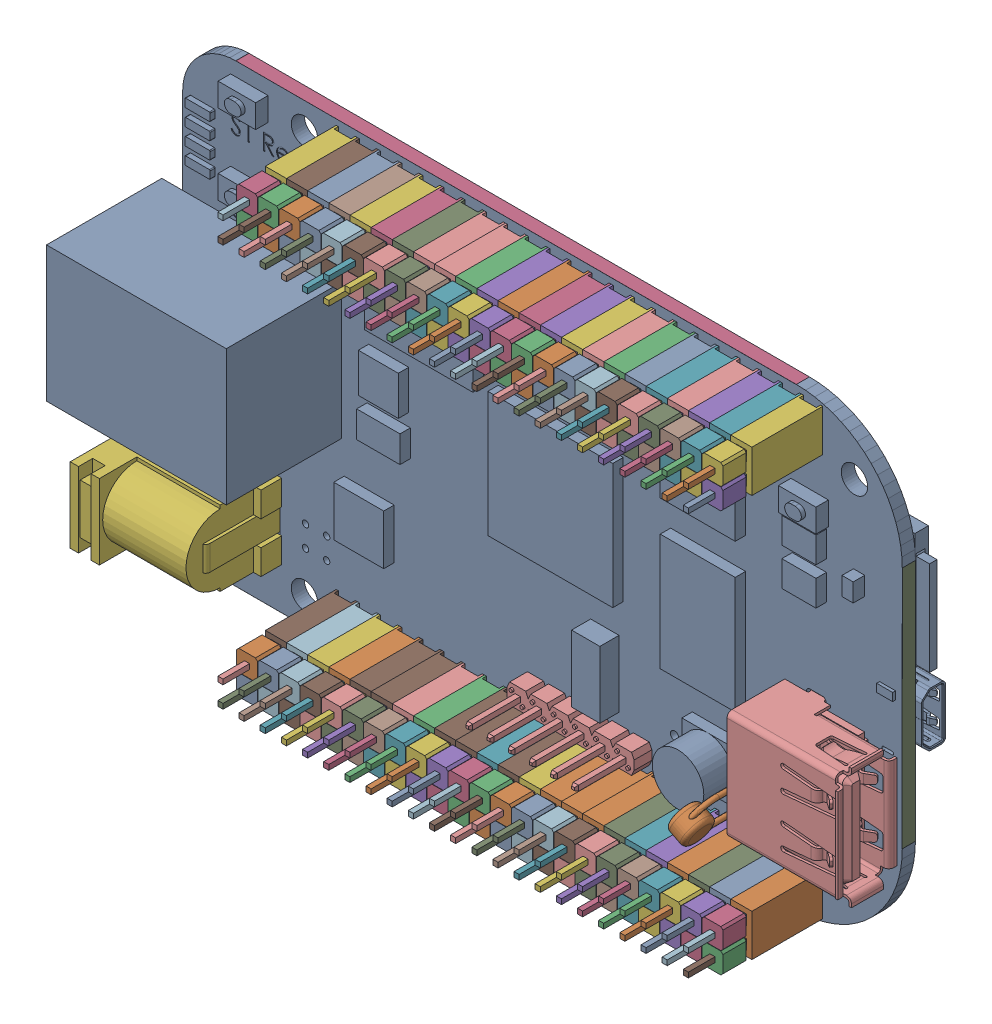
SolidWorks assembly U200PCB, configuration Default. Lengths in mm.
Overall size (90.45 54.71 20.73).
369 component instances, 3 part files, 0 mates.
Components (placement in the parent):
- User_Library-BEAGLEBONE_BLACK-1: User_Library-BEAGLEBONE_BLACK [Default] at (76.2001 76.2001 -13.6333) size (90.45 54.71 19.4)
- 761618560-1: 761618560 [Default] at (151.7651 128.9051 -4.4638) size (2.5 2.5 2.8)
  - Extruded_21-1: Extruded_21 [Default] at origin size (2.5 2.5 2.8)
- 761618560-2: 761618560 [Default] at (149.2251 128.9051 -4.4638) size (2.5 2.5 2.8)
  - Extruded_21-1: Extruded_21 [Default] at origin size (2.5 2.5 2.8)
- 761618560-3: 761618560 [Default] at (146.6851 128.9051 -4.4638) size (2.5 2.5 2.8)
  - Extruded_21-1: Extruded_21 [Default] at origin size (2.5 2.5 2.8)
- 761618560-4: 761618560 [Default] at (144.1451 128.9051 -4.4638) size (2.5 2.5 2.8)
  - Extruded_21-1: Extruded_21 [Default] at origin size (2.5 2.5 2.8)
- 761618560-5: 761618560 [Default] at (141.6051 128.9051 -4.4638) size (2.5 2.5 2.8)
  - Extruded_21-1: Extruded_21 [Default] at origin size (2.5 2.5 2.8)
- 761618560-6: 761618560 [Default] at (139.0651 128.9051 -4.4638) size (2.5 2.5 2.8)
  - Extruded_21-1: Extruded_21 [Default] at origin size (2.5 2.5 2.8)
- 761618560-7: 761618560 [Default] at (136.5251 128.9051 -4.4638) size (2.5 2.5 2.8)
  - Extruded_21-1: Extruded_21 [Default] at origin size (2.5 2.5 2.8)
- 761618560-8: 761618560 [Default] at (133.9851 128.9051 -4.4638) size (2.5 2.5 2.8)
  - Extruded_21-1: Extruded_21 [Default] at origin size (2.5 2.5 2.8)
- 761618560-9: 761618560 [Default] at (131.4451 128.9051 -4.4638) size (2.5 2.5 2.8)
  - Extruded_21-1: Extruded_21 [Default] at origin size (2.5 2.5 2.8)
- 761618560-10: 761618560 [Default] at (128.9051 128.9051 -4.4638) size (2.5 2.5 2.8)
  - Extruded_21-1: Extruded_21 [Default] at origin size (2.5 2.5 2.8)
- 761618560-11: 761618560 [Default] at (126.3651 128.9051 -4.4638) size (2.5 2.5 2.8)
  - Extruded_21-1: Extruded_21 [Default] at origin size (2.5 2.5 2.8)
- 761618560-12: 761618560 [Default] at (123.8251 128.9051 -4.4638) size (2.5 2.5 2.8)
  - Extruded_21-1: Extruded_21 [Default] at origin size (2.5 2.5 2.8)
- 761618560-13: 761618560 [Default] at (121.2851 128.9051 -4.4638) size (2.5 2.5 2.8)
  - Extruded_21-1: Extruded_21 [Default] at origin size (2.5 2.5 2.8)
- 761618560-14: 761618560 [Default] at (118.7451 128.9051 -4.4638) size (2.5 2.5 2.8)
  - Extruded_21-1: Extruded_21 [Default] at origin size (2.5 2.5 2.8)
- 761618560-15: 761618560 [Default] at (116.2051 128.9051 -4.4638) size (2.5 2.5 2.8)
  - Extruded_21-1: Extruded_21 [Default] at origin size (2.5 2.5 2.8)
- 761618560-16: 761618560 [Default] at (113.6651 128.9051 -4.4638) size (2.5 2.5 2.8)
  - Extruded_21-1: Extruded_21 [Default] at origin size (2.5 2.5 2.8)
- 761618560-17: 761618560 [Default] at (111.1251 128.9051 -4.4638) size (2.5 2.5 2.8)
  - Extruded_21-1: Extruded_21 [Default] at origin size (2.5 2.5 2.8)
- 761618560-18: 761618560 [Default] at (108.5851 128.9051 -4.4638) size (2.5 2.5 2.8)
  - Extruded_21-1: Extruded_21 [Default] at origin size (2.5 2.5 2.8)
- 761618560-19: 761618560 [Default] at (106.0451 128.9051 -4.4638) size (2.5 2.5 2.8)
  - Extruded_21-1: Extruded_21 [Default] at origin size (2.5 2.5 2.8)
- 761618560-20: 761618560 [Default] at (103.5051 128.9051 -4.4638) size (2.5 2.5 2.8)
  - Extruded_21-1: Extruded_21 [Default] at origin size (2.5 2.5 2.8)
- 761618560-21: 761618560 [Default] at (100.9651 128.9051 -4.4638) size (2.5 2.5 2.8)
  - Extruded_21-1: Extruded_21 [Default] at origin size (2.5 2.5 2.8)
- 761618560-22: 761618560 [Default] at (98.4251 128.9051 -4.4638) size (2.5 2.5 2.8)
  - Extruded_21-1: Extruded_21 [Default] at origin size (2.5 2.5 2.8)
- 761618560-23: 761618560 [Default] at (95.8851 128.9051 -4.4638) size (2.5 2.5 2.8)
  - Extruded_21-1: Extruded_21 [Default] at origin size (2.5 2.5 2.8)
- 761618560-24: 761618560 [Default] at (151.7651 126.3651 -4.4638) size (2.5 2.5 2.8)
  - Extruded_21-1: Extruded_21 [Default] at origin size (2.5 2.5 2.8)
- 761618560-25: 761618560 [Default] at (149.2251 126.3651 -4.4638) size (2.5 2.5 2.8)
  - Extruded_21-1: Extruded_21 [Default] at origin size (2.5 2.5 2.8)
- 761618560-26: 761618560 [Default] at (146.6851 126.3651 -4.4638) size (2.5 2.5 2.8)
  - Extruded_21-1: Extruded_21 [Default] at origin size (2.5 2.5 2.8)
- 761618560-27: 761618560 [Default] at (144.1451 126.3651 -4.4638) size (2.5 2.5 2.8)
  - Extruded_21-1: Extruded_21 [Default] at origin size (2.5 2.5 2.8)
- 761618560-28: 761618560 [Default] at (141.6051 126.3651 -4.4638) size (2.5 2.5 2.8)
  - Extruded_21-1: Extruded_21 [Default] at origin size (2.5 2.5 2.8)
- 761618560-29: 761618560 [Default] at (139.0651 126.3651 -4.4638) size (2.5 2.5 2.8)
  - Extruded_21-1: Extruded_21 [Default] at origin size (2.5 2.5 2.8)
- 761618560-30: 761618560 [Default] at (136.5251 126.3651 -4.4638) size (2.5 2.5 2.8)
  - Extruded_21-1: Extruded_21 [Default] at origin size (2.5 2.5 2.8)
- 761618560-31: 761618560 [Default] at (133.9851 126.3651 -4.4638) size (2.5 2.5 2.8)
  - Extruded_21-1: Extruded_21 [Default] at origin size (2.5 2.5 2.8)
- 761618560-32: 761618560 [Default] at (131.4451 126.3651 -4.4638) size (2.5 2.5 2.8)
  - Extruded_21-1: Extruded_21 [Default] at origin size (2.5 2.5 2.8)
- 761618560-33: 761618560 [Default] at (128.9051 126.3651 -4.4638) size (2.5 2.5 2.8)
  - Extruded_21-1: Extruded_21 [Default] at origin size (2.5 2.5 2.8)
- 761618560-34: 761618560 [Default] at (126.3651 126.3651 -4.4638) size (2.5 2.5 2.8)
  - Extruded_21-1: Extruded_21 [Default] at origin size (2.5 2.5 2.8)
- 761618560-35: 761618560 [Default] at (123.8251 126.3651 -4.4638) size (2.5 2.5 2.8)
  - Extruded_21-1: Extruded_21 [Default] at origin size (2.5 2.5 2.8)
- 761618560-36: 761618560 [Default] at (121.2851 126.3651 -4.4638) size (2.5 2.5 2.8)
  - Extruded_21-1: Extruded_21 [Default] at origin size (2.5 2.5 2.8)
- 761618560-37: 761618560 [Default] at (118.7451 126.3651 -4.4638) size (2.5 2.5 2.8)
  - Extruded_21-1: Extruded_21 [Default] at origin size (2.5 2.5 2.8)
- 761618560-38: 761618560 [Default] at (116.2051 126.3651 -4.4638) size (2.5 2.5 2.8)
  - Extruded_21-1: Extruded_21 [Default] at origin size (2.5 2.5 2.8)
- 761618560-39: 761618560 [Default] at (113.6651 126.3651 -4.4638) size (2.5 2.5 2.8)
  - Extruded_21-1: Extruded_21 [Default] at origin size (2.5 2.5 2.8)
- 761618560-40: 761618560 [Default] at (111.1251 126.3651 -4.4638) size (2.5 2.5 2.8)
  - Extruded_21-1: Extruded_21 [Default] at origin size (2.5 2.5 2.8)
- 761618560-41: 761618560 [Default] at (108.5851 126.3651 -4.4638) size (2.5 2.5 2.8)
  - Extruded_21-1: Extruded_21 [Default] at origin size (2.5 2.5 2.8)
- 761618560-42: 761618560 [Default] at (106.0451 126.3651 -4.4638) size (2.5 2.5 2.8)
  - Extruded_21-1: Extruded_21 [Default] at origin size (2.5 2.5 2.8)
- 761618560-43: 761618560 [Default] at (103.5051 126.3651 -4.4638) size (2.5 2.5 2.8)
  - Extruded_21-1: Extruded_21 [Default] at origin size (2.5 2.5 2.8)
- 761618560-44: 761618560 [Default] at (100.9651 126.3651 -4.4638) size (2.5 2.5 2.8)
  - Extruded_21-1: Extruded_21 [Default] at origin size (2.5 2.5 2.8)
- 761618560-45: 761618560 [Default] at (98.4251 126.3651 -4.4638) size (2.5 2.5 2.8)
  - Extruded_21-1: Extruded_21 [Default] at origin size (2.5 2.5 2.8)
- 761618560-46: 761618560 [Default] at (95.8851 126.3651 -4.4638) size (2.5 2.5 2.8)
  - Extruded_21-1: Extruded_21 [Default] at origin size (2.5 2.5 2.8)
- 761618560-47: 761618560 [Default] at (151.7651 80.6451 -4.4638) size (2.5 2.5 2.8)
  - Extruded_21-1: Extruded_21 [Default] at origin size (2.5 2.5 2.8)
- 761618560-48: 761618560 [Default] at (149.2251 80.6451 -4.4638) size (2.5 2.5 2.8)
  - Extruded_21-1: Extruded_21 [Default] at origin size (2.5 2.5 2.8)
- 761618560-49: 761618560 [Default] at (146.6851 80.6451 -4.4638) size (2.5 2.5 2.8)
  - Extruded_21-1: Extruded_21 [Default] at origin size (2.5 2.5 2.8)
- 761618560-50: 761618560 [Default] at (144.1451 80.6451 -4.4638) size (2.5 2.5 2.8)
  - Extruded_21-1: Extruded_21 [Default] at origin size (2.5 2.5 2.8)
- 761618560-51: 761618560 [Default] at (141.6051 80.6451 -4.4638) size (2.5 2.5 2.8)
  - Extruded_21-1: Extruded_21 [Default] at origin size (2.5 2.5 2.8)
- 761618560-52: 761618560 [Default] at (139.0651 80.6451 -4.4638) size (2.5 2.5 2.8)
  - Extruded_21-1: Extruded_21 [Default] at origin size (2.5 2.5 2.8)
- 761618560-53: 761618560 [Default] at (136.5251 80.6451 -4.4638) size (2.5 2.5 2.8)
  - Extruded_21-1: Extruded_21 [Default] at origin size (2.5 2.5 2.8)
- 761618560-54: 761618560 [Default] at (133.9851 80.6451 -4.4638) size (2.5 2.5 2.8)
  - Extruded_21-1: Extruded_21 [Default] at origin size (2.5 2.5 2.8)
- 761618560-55: 761618560 [Default] at (131.4451 80.6451 -4.4638) size (2.5 2.5 2.8)
  - Extruded_21-1: Extruded_21 [Default] at origin size (2.5 2.5 2.8)
- 761618560-56: 761618560 [Default] at (128.9051 80.6451 -4.4638) size (2.5 2.5 2.8)
  - Extruded_21-1: Extruded_21 [Default] at origin size (2.5 2.5 2.8)
- 761618560-57: 761618560 [Default] at (126.3651 80.6451 -4.4638) size (2.5 2.5 2.8)
  - Extruded_21-1: Extruded_21 [Default] at origin size (2.5 2.5 2.8)
- 761618560-58: 761618560 [Default] at (123.8251 80.6451 -4.4638) size (2.5 2.5 2.8)
  - Extruded_21-1: Extruded_21 [Default] at origin size (2.5 2.5 2.8)
- 761618560-59: 761618560 [Default] at (121.2851 80.6451 -4.4638) size (2.5 2.5 2.8)
  - Extruded_21-1: Extruded_21 [Default] at origin size (2.5 2.5 2.8)
- 761618560-60: 761618560 [Default] at (118.7451 80.6451 -4.4638) size (2.5 2.5 2.8)
  - Extruded_21-1: Extruded_21 [Default] at origin size (2.5 2.5 2.8)
- 761618560-61: 761618560 [Default] at (116.2051 80.6451 -4.4638) size (2.5 2.5 2.8)
  - Extruded_21-1: Extruded_21 [Default] at origin size (2.5 2.5 2.8)
- 761618560-62: 761618560 [Default] at (113.6651 80.6451 -4.4638) size (2.5 2.5 2.8)
  - Extruded_21-1: Extruded_21 [Default] at origin size (2.5 2.5 2.8)
- 761618560-63: 761618560 [Default] at (111.1251 80.6451 -4.4638) size (2.5 2.5 2.8)
  - Extruded_21-1: Extruded_21 [Default] at origin size (2.5 2.5 2.8)
- 761618560-64: 761618560 [Default] at (108.5851 80.6451 -4.4638) size (2.5 2.5 2.8)
  - Extruded_21-1: Extruded_21 [Default] at origin size (2.5 2.5 2.8)
- 761618560-65: 761618560 [Default] at (106.0451 80.6451 -4.4638) size (2.5 2.5 2.8)
  - Extruded_21-1: Extruded_21 [Default] at origin size (2.5 2.5 2.8)
- 761618560-66: 761618560 [Default] at (103.5051 80.6451 -4.4638) size (2.5 2.5 2.8)
  - Extruded_21-1: Extruded_21 [Default] at origin size (2.5 2.5 2.8)
- 761618560-67: 761618560 [Default] at (100.9651 80.6451 -4.4638) size (2.5 2.5 2.8)
  - Extruded_21-1: Extruded_21 [Default] at origin size (2.5 2.5 2.8)
- 761618560-68: 761618560 [Default] at (98.4251 80.6451 -4.4638) size (2.5 2.5 2.8)
  - Extruded_21-1: Extruded_21 [Default] at origin size (2.5 2.5 2.8)
- 761618560-69: 761618560 [Default] at (95.8851 80.6451 -4.4638) size (2.5 2.5 2.8)
  - Extruded_21-1: Extruded_21 [Default] at origin size (2.5 2.5 2.8)
- 761618560-70: 761618560 [Default] at (151.7651 78.1051 -4.4638) size (2.5 2.5 2.8)
  - Extruded_21-1: Extruded_21 [Default] at origin size (2.5 2.5 2.8)
- 761618560-71: 761618560 [Default] at (149.2251 78.1051 -4.4638) size (2.5 2.5 2.8)
  - Extruded_21-1: Extruded_21 [Default] at origin size (2.5 2.5 2.8)
- 761618560-72: 761618560 [Default] at (146.6851 78.1051 -4.4638) size (2.5 2.5 2.8)
  - Extruded_21-1: Extruded_21 [Default] at origin size (2.5 2.5 2.8)
- 761618560-73: 761618560 [Default] at (144.1451 78.1051 -4.4638) size (2.5 2.5 2.8)
  - Extruded_21-1: Extruded_21 [Default] at origin size (2.5 2.5 2.8)
- 761618560-74: 761618560 [Default] at (141.6051 78.1051 -4.4638) size (2.5 2.5 2.8)
  - Extruded_21-1: Extruded_21 [Default] at origin size (2.5 2.5 2.8)
- 761618560-75: 761618560 [Default] at (139.0651 78.1051 -4.4638) size (2.5 2.5 2.8)
  - Extruded_21-1: Extruded_21 [Default] at origin size (2.5 2.5 2.8)
- 761618560-76: 761618560 [Default] at (136.5251 78.1051 -4.4638) size (2.5 2.5 2.8)
  - Extruded_21-1: Extruded_21 [Default] at origin size (2.5 2.5 2.8)
- 761618560-77: 761618560 [Default] at (133.9851 78.1051 -4.4638) size (2.5 2.5 2.8)
  - Extruded_21-1: Extruded_21 [Default] at origin size (2.5 2.5 2.8)
- 761618560-78: 761618560 [Default] at (131.4451 78.1051 -4.4638) size (2.5 2.5 2.8)
  - Extruded_21-1: Extruded_21 [Default] at origin size (2.5 2.5 2.8)
- 761618560-79: 761618560 [Default] at (128.9051 78.1051 -4.4638) size (2.5 2.5 2.8)
  - Extruded_21-1: Extruded_21 [Default] at origin size (2.5 2.5 2.8)
- 761618560-80: 761618560 [Default] at (126.3651 78.1051 -4.4638) size (2.5 2.5 2.8)
  - Extruded_21-1: Extruded_21 [Default] at origin size (2.5 2.5 2.8)
- 761618560-81: 761618560 [Default] at (123.8251 78.1051 -4.4638) size (2.5 2.5 2.8)
  - Extruded_21-1: Extruded_21 [Default] at origin size (2.5 2.5 2.8)
- 761618560-82: 761618560 [Default] at (121.2851 78.1051 -4.4638) size (2.5 2.5 2.8)
  - Extruded_21-1: Extruded_21 [Default] at origin size (2.5 2.5 2.8)
- 761618560-83: 761618560 [Default] at (118.7451 78.1051 -4.4638) size (2.5 2.5 2.8)
  - Extruded_21-1: Extruded_21 [Default] at origin size (2.5 2.5 2.8)
- 761618560-84: 761618560 [Default] at (116.2051 78.1051 -4.4638) size (2.5 2.5 2.8)
  - Extruded_21-1: Extruded_21 [Default] at origin size (2.5 2.5 2.8)
- 761618560-85: 761618560 [Default] at (113.6651 78.1051 -4.4638) size (2.5 2.5 2.8)
  - Extruded_21-1: Extruded_21 [Default] at origin size (2.5 2.5 2.8)
- 761618560-86: 761618560 [Default] at (111.1251 78.1051 -4.4638) size (2.5 2.5 2.8)
  - Extruded_21-1: Extruded_21 [Default] at origin size (2.5 2.5 2.8)
- 761618560-87: 761618560 [Default] at (108.5851 78.1051 -4.4638) size (2.5 2.5 2.8)
  - Extruded_21-1: Extruded_21 [Default] at origin size (2.5 2.5 2.8)
- 761618560-88: 761618560 [Default] at (106.0451 78.1051 -4.4638) size (2.5 2.5 2.8)
  - Extruded_21-1: Extruded_21 [Default] at origin size (2.5 2.5 2.8)
- 761618560-89: 761618560 [Default] at (103.5051 78.1051 -4.4638) size (2.5 2.5 2.8)
  - Extruded_21-1: Extruded_21 [Default] at origin size (2.5 2.5 2.8)
- 761618560-90: 761618560 [Default] at (100.9651 78.1051 -4.4638) size (2.5 2.5 2.8)
  - Extruded_21-1: Extruded_21 [Default] at origin size (2.5 2.5 2.8)
- 761618560-91: 761618560 [Default] at (98.4251 78.1051 -4.4638) size (2.5 2.5 2.8)
  - Extruded_21-1: Extruded_21 [Default] at origin size (2.5 2.5 2.8)
- 761618560-92: 761618560 [Default] at (95.8851 78.1051 -4.4638) size (2.5 2.5 2.8)
  - Extruded_21-1: Extruded_21 [Default] at origin size (2.5 2.5 2.8)
- 761616656-1: 761616656 [Default] at (151.7651 128.9051 -11.1638) size (0.61 0.61 12.7)
  - Extruded_22-1: Extruded_22 [Default] at origin size (0.61 0.61 12.7)
- 761616656-2: 761616656 [Default] at (149.2251 128.9051 -11.1638) size (0.61 0.61 12.7)
  - Extruded_22-1: Extruded_22 [Default] at origin size (0.61 0.61 12.7)
- 761616656-3: 761616656 [Default] at (146.6851 128.9051 -11.1638) size (0.61 0.61 12.7)
  - Extruded_22-1: Extruded_22 [Default] at origin size (0.61 0.61 12.7)
- 761616656-4: 761616656 [Default] at (144.1451 128.9051 -11.1638) size (0.61 0.61 12.7)
  - Extruded_22-1: Extruded_22 [Default] at origin size (0.61 0.61 12.7)
- 761616656-5: 761616656 [Default] at (141.6051 128.9051 -11.1638) size (0.61 0.61 12.7)
  - Extruded_22-1: Extruded_22 [Default] at origin size (0.61 0.61 12.7)
- 761616656-6: 761616656 [Default] at (139.0651 128.9051 -11.1638) size (0.61 0.61 12.7)
  - Extruded_22-1: Extruded_22 [Default] at origin size (0.61 0.61 12.7)
- 761616656-7: 761616656 [Default] at (136.5251 128.9051 -11.1638) size (0.61 0.61 12.7)
  - Extruded_22-1: Extruded_22 [Default] at origin size (0.61 0.61 12.7)
- 761616656-8: 761616656 [Default] at (133.9851 128.9051 -11.1638) size (0.61 0.61 12.7)
  - Extruded_22-1: Extruded_22 [Default] at origin size (0.61 0.61 12.7)
- 761616656-9: 761616656 [Default] at (131.4451 128.9051 -11.1638) size (0.61 0.61 12.7)
  - Extruded_22-1: Extruded_22 [Default] at origin size (0.61 0.61 12.7)
- 761616656-10: 761616656 [Default] at (128.9051 128.9051 -11.1638) size (0.61 0.61 12.7)
  - Extruded_22-1: Extruded_22 [Default] at origin size (0.61 0.61 12.7)
- 761616656-11: 761616656 [Default] at (126.3651 128.9051 -11.1638) size (0.61 0.61 12.7)
  - Extruded_22-1: Extruded_22 [Default] at origin size (0.61 0.61 12.7)
- 761616656-12: 761616656 [Default] at (123.8251 128.9051 -11.1638) size (0.61 0.61 12.7)
  - Extruded_22-1: Extruded_22 [Default] at origin size (0.61 0.61 12.7)
- 761616656-13: 761616656 [Default] at (121.2851 128.9051 -11.1638) size (0.61 0.61 12.7)
  - Extruded_22-1: Extruded_22 [Default] at origin size (0.61 0.61 12.7)
- 761616656-14: 761616656 [Default] at (118.7451 128.9051 -11.1638) size (0.61 0.61 12.7)
  - Extruded_22-1: Extruded_22 [Default] at origin size (0.61 0.61 12.7)
- 761616656-15: 761616656 [Default] at (116.2051 128.9051 -11.1638) size (0.61 0.61 12.7)
  - Extruded_22-1: Extruded_22 [Default] at origin size (0.61 0.61 12.7)
- 761616656-16: 761616656 [Default] at (113.6651 128.9051 -11.1638) size (0.61 0.61 12.7)
  - Extruded_22-1: Extruded_22 [Default] at origin size (0.61 0.61 12.7)
- 761616656-17: 761616656 [Default] at (111.1251 128.9051 -11.1638) size (0.61 0.61 12.7)
  - Extruded_22-1: Extruded_22 [Default] at origin size (0.61 0.61 12.7)
- 761616656-18: 761616656 [Default] at (108.5851 128.9051 -11.1638) size (0.61 0.61 12.7)
  - Extruded_22-1: Extruded_22 [Default] at origin size (0.61 0.61 12.7)
- 761616656-19: 761616656 [Default] at (106.0451 128.9051 -11.1638) size (0.61 0.61 12.7)
  - Extruded_22-1: Extruded_22 [Default] at origin size (0.61 0.61 12.7)
- 761616656-20: 761616656 [Default] at (103.5051 128.9051 -11.1638) size (0.61 0.61 12.7)
  - Extruded_22-1: Extruded_22 [Default] at origin size (0.61 0.61 12.7)
- 761616656-21: 761616656 [Default] at (100.9651 128.9051 -11.1638) size (0.61 0.61 12.7)
  - Extruded_22-1: Extruded_22 [Default] at origin size (0.61 0.61 12.7)
- 761616656-22: 761616656 [Default] at (98.4251 128.9051 -11.1638) size (0.61 0.61 12.7)
  - Extruded_22-1: Extruded_22 [Default] at origin size (0.61 0.61 12.7)
- 761616656-23: 761616656 [Default] at (95.8851 128.9051 -11.1638) size (0.61 0.61 12.7)
  - Extruded_22-1: Extruded_22 [Default] at origin size (0.61 0.61 12.7)
- 761616656-24: 761616656 [Default] at (151.7651 126.3651 -11.1638) size (0.61 0.61 12.7)
  - Extruded_22-1: Extruded_22 [Default] at origin size (0.61 0.61 12.7)
- 761616656-25: 761616656 [Default] at (149.2251 126.3651 -11.1638) size (0.61 0.61 12.7)
  - Extruded_22-1: Extruded_22 [Default] at origin size (0.61 0.61 12.7)
- 761616656-26: 761616656 [Default] at (146.6851 126.3651 -11.1638) size (0.61 0.61 12.7)
  - Extruded_22-1: Extruded_22 [Default] at origin size (0.61 0.61 12.7)
- 761616656-27: 761616656 [Default] at (144.1451 126.3651 -11.1638) size (0.61 0.61 12.7)
  - Extruded_22-1: Extruded_22 [Default] at origin size (0.61 0.61 12.7)
- 761616656-28: 761616656 [Default] at (141.6051 126.3651 -11.1638) size (0.61 0.61 12.7)
  - Extruded_22-1: Extruded_22 [Default] at origin size (0.61 0.61 12.7)
- 761616656-29: 761616656 [Default] at (139.0651 126.3651 -11.1638) size (0.61 0.61 12.7)
  - Extruded_22-1: Extruded_22 [Default] at origin size (0.61 0.61 12.7)
- 761616656-30: 761616656 [Default] at (136.5251 126.3651 -11.1638) size (0.61 0.61 12.7)
  - Extruded_22-1: Extruded_22 [Default] at origin size (0.61 0.61 12.7)
- 761616656-31: 761616656 [Default] at (133.9851 126.3651 -11.1638) size (0.61 0.61 12.7)
  - Extruded_22-1: Extruded_22 [Default] at origin size (0.61 0.61 12.7)
- 761616656-32: 761616656 [Default] at (131.4451 126.3651 -11.1638) size (0.61 0.61 12.7)
  - Extruded_22-1: Extruded_22 [Default] at origin size (0.61 0.61 12.7)
- 761616656-33: 761616656 [Default] at (128.9051 126.3651 -11.1638) size (0.61 0.61 12.7)
  - Extruded_22-1: Extruded_22 [Default] at origin size (0.61 0.61 12.7)
- 761616656-34: 761616656 [Default] at (126.3651 126.3651 -11.1638) size (0.61 0.61 12.7)
  - Extruded_22-1: Extruded_22 [Default] at origin size (0.61 0.61 12.7)
- 761616656-35: 761616656 [Default] at (123.8251 126.3651 -11.1638) size (0.61 0.61 12.7)
  - Extruded_22-1: Extruded_22 [Default] at origin size (0.61 0.61 12.7)
- 761616656-36: 761616656 [Default] at (121.2851 126.3651 -11.1638) size (0.61 0.61 12.7)
  - Extruded_22-1: Extruded_22 [Default] at origin size (0.61 0.61 12.7)
- 761616656-37: 761616656 [Default] at (118.7451 126.3651 -11.1638) size (0.61 0.61 12.7)
  - Extruded_22-1: Extruded_22 [Default] at origin size (0.61 0.61 12.7)
- 761616656-38: 761616656 [Default] at (116.2051 126.3651 -11.1638) size (0.61 0.61 12.7)
  - Extruded_22-1: Extruded_22 [Default] at origin size (0.61 0.61 12.7)
- 761616656-39: 761616656 [Default] at (113.6651 126.3651 -11.1638) size (0.61 0.61 12.7)
  - Extruded_22-1: Extruded_22 [Default] at origin size (0.61 0.61 12.7)
- 761616656-40: 761616656 [Default] at (111.1251 126.3651 -11.1638) size (0.61 0.61 12.7)
  - Extruded_22-1: Extruded_22 [Default] at origin size (0.61 0.61 12.7)
- 761616656-41: 761616656 [Default] at (108.5851 126.3651 -11.1638) size (0.61 0.61 12.7)
  - Extruded_22-1: Extruded_22 [Default] at origin size (0.61 0.61 12.7)
- 761616656-42: 761616656 [Default] at (106.0451 126.3651 -11.1638) size (0.61 0.61 12.7)
  - Extruded_22-1: Extruded_22 [Default] at origin size (0.61 0.61 12.7)
- 761616656-43: 761616656 [Default] at (103.5051 126.3651 -11.1638) size (0.61 0.61 12.7)
  - Extruded_22-1: Extruded_22 [Default] at origin size (0.61 0.61 12.7)
- 761616656-44: 761616656 [Default] at (100.9651 126.3651 -11.1638) size (0.61 0.61 12.7)
  - Extruded_22-1: Extruded_22 [Default] at origin size (0.61 0.61 12.7)
- 761616656-45: 761616656 [Default] at (98.4251 126.3651 -11.1638) size (0.61 0.61 12.7)
  - Extruded_22-1: Extruded_22 [Default] at origin size (0.61 0.61 12.7)
- 761616656-46: 761616656 [Default] at (95.8851 126.3651 -11.1638) size (0.61 0.61 12.7)
  - Extruded_22-1: Extruded_22 [Default] at origin size (0.61 0.61 12.7)
- 761616656-47: 761616656 [Default] at (151.7651 80.6451 -11.1638) size (0.61 0.61 12.7)
  - Extruded_22-1: Extruded_22 [Default] at origin size (0.61 0.61 12.7)
- 761616656-48: 761616656 [Default] at (149.2251 80.6451 -11.1638) size (0.61 0.61 12.7)
  - Extruded_22-1: Extruded_22 [Default] at origin size (0.61 0.61 12.7)
- 761616656-49: 761616656 [Default] at (146.6851 80.6451 -11.1638) size (0.61 0.61 12.7)
  - Extruded_22-1: Extruded_22 [Default] at origin size (0.61 0.61 12.7)
- 761616656-50: 761616656 [Default] at (144.1451 80.6451 -11.1638) size (0.61 0.61 12.7)
  - Extruded_22-1: Extruded_22 [Default] at origin size (0.61 0.61 12.7)
- 761616656-51: 761616656 [Default] at (141.6051 80.6451 -11.1638) size (0.61 0.61 12.7)
  - Extruded_22-1: Extruded_22 [Default] at origin size (0.61 0.61 12.7)
- 761616656-52: 761616656 [Default] at (139.0651 80.6451 -11.1638) size (0.61 0.61 12.7)
  - Extruded_22-1: Extruded_22 [Default] at origin size (0.61 0.61 12.7)
- 761616656-53: 761616656 [Default] at (136.5251 80.6451 -11.1638) size (0.61 0.61 12.7)
  - Extruded_22-1: Extruded_22 [Default] at origin size (0.61 0.61 12.7)
- 761616656-54: 761616656 [Default] at (133.9851 80.6451 -11.1638) size (0.61 0.61 12.7)
  - Extruded_22-1: Extruded_22 [Default] at origin size (0.61 0.61 12.7)
- 761616656-55: 761616656 [Default] at (131.4451 80.6451 -11.1638) size (0.61 0.61 12.7)
  - Extruded_22-1: Extruded_22 [Default] at origin size (0.61 0.61 12.7)
- 761616656-56: 761616656 [Default] at (128.9051 80.6451 -11.1638) size (0.61 0.61 12.7)
  - Extruded_22-1: Extruded_22 [Default] at origin size (0.61 0.61 12.7)
- 761616656-57: 761616656 [Default] at (126.3651 80.6451 -11.1638) size (0.61 0.61 12.7)
  - Extruded_22-1: Extruded_22 [Default] at origin size (0.61 0.61 12.7)
- 761616656-58: 761616656 [Default] at (123.8251 80.6451 -11.1638) size (0.61 0.61 12.7)
  - Extruded_22-1: Extruded_22 [Default] at origin size (0.61 0.61 12.7)
- 761616656-59: 761616656 [Default] at (121.2851 80.6451 -11.1638) size (0.61 0.61 12.7)
  - Extruded_22-1: Extruded_22 [Default] at origin size (0.61 0.61 12.7)
- 761616656-60: 761616656 [Default] at (118.7451 80.6451 -11.1638) size (0.61 0.61 12.7)
  - Extruded_22-1: Extruded_22 [Default] at origin size (0.61 0.61 12.7)
- 761616656-61: 761616656 [Default] at (116.2051 80.6451 -11.1638) size (0.61 0.61 12.7)
  - Extruded_22-1: Extruded_22 [Default] at origin size (0.61 0.61 12.7)
- 761616656-62: 761616656 [Default] at (113.6651 80.6451 -11.1638) size (0.61 0.61 12.7)
  - Extruded_22-1: Extruded_22 [Default] at origin size (0.61 0.61 12.7)
- 761616656-63: 761616656 [Default] at (111.1251 80.6451 -11.1638) size (0.61 0.61 12.7)
  - Extruded_22-1: Extruded_22 [Default] at origin size (0.61 0.61 12.7)
- 761616656-64: 761616656 [Default] at (108.5851 80.6451 -11.1638) size (0.61 0.61 12.7)
  - Extruded_22-1: Extruded_22 [Default] at origin size (0.61 0.61 12.7)
- 761616656-65: 761616656 [Default] at (106.0451 80.6451 -11.1638) size (0.61 0.61 12.7)
  - Extruded_22-1: Extruded_22 [Default] at origin size (0.61 0.61 12.7)
- 761616656-66: 761616656 [Default] at (103.5051 80.6451 -11.1638) size (0.61 0.61 12.7)
  - Extruded_22-1: Extruded_22 [Default] at origin size (0.61 0.61 12.7)
- 761616656-67: 761616656 [Default] at (100.9651 80.6451 -11.1638) size (0.61 0.61 12.7)
  - Extruded_22-1: Extruded_22 [Default] at origin size (0.61 0.61 12.7)
- 761616656-68: 761616656 [Default] at (98.4251 80.6451 -11.1638) size (0.61 0.61 12.7)
  - Extruded_22-1: Extruded_22 [Default] at origin size (0.61 0.61 12.7)
- 761616656-69: 761616656 [Default] at (95.8851 80.6451 -11.1638) size (0.61 0.61 12.7)
  - Extruded_22-1: Extruded_22 [Default] at origin size (0.61 0.61 12.7)
- 761616656-70: 761616656 [Default] at (151.7651 78.1051 -11.1638) size (0.61 0.61 12.7)
  - Extruded_22-1: Extruded_22 [Default] at origin size (0.61 0.61 12.7)
- 761616656-71: 761616656 [Default] at (149.2251 78.1051 -11.1638) size (0.61 0.61 12.7)
  - Extruded_22-1: Extruded_22 [Default] at origin size (0.61 0.61 12.7)
- 761616656-72: 761616656 [Default] at (146.6851 78.1051 -11.1638) size (0.61 0.61 12.7)
  - Extruded_22-1: Extruded_22 [Default] at origin size (0.61 0.61 12.7)
- 761616656-73: 761616656 [Default] at (144.1451 78.1051 -11.1638) size (0.61 0.61 12.7)
  - Extruded_22-1: Extruded_22 [Default] at origin size (0.61 0.61 12.7)
- 761616656-74: 761616656 [Default] at (141.6051 78.1051 -11.1638) size (0.61 0.61 12.7)
  - Extruded_22-1: Extruded_22 [Default] at origin size (0.61 0.61 12.7)
- 761616656-75: 761616656 [Default] at (139.0651 78.1051 -11.1638) size (0.61 0.61 12.7)
  - Extruded_22-1: Extruded_22 [Default] at origin size (0.61 0.61 12.7)
- 761616656-76: 761616656 [Default] at (136.5251 78.1051 -11.1638) size (0.61 0.61 12.7)
  - Extruded_22-1: Extruded_22 [Default] at origin size (0.61 0.61 12.7)
- 761616656-77: 761616656 [Default] at (133.9851 78.1051 -11.1638) size (0.61 0.61 12.7)
  - Extruded_22-1: Extruded_22 [Default] at origin size (0.61 0.61 12.7)
- 761616656-78: 761616656 [Default] at (131.4451 78.1051 -11.1638) size (0.61 0.61 12.7)
  - Extruded_22-1: Extruded_22 [Default] at origin size (0.61 0.61 12.7)
- 761616656-79: 761616656 [Default] at (128.9051 78.1051 -11.1638) size (0.61 0.61 12.7)
  - Extruded_22-1: Extruded_22 [Default] at origin size (0.61 0.61 12.7)
- 761616656-80: 761616656 [Default] at (126.3651 78.1051 -11.1638) size (0.61 0.61 12.7)
  - Extruded_22-1: Extruded_22 [Default] at origin size (0.61 0.61 12.7)
- 761616656-81: 761616656 [Default] at (123.8251 78.1051 -11.1638) size (0.61 0.61 12.7)
  - Extruded_22-1: Extruded_22 [Default] at origin size (0.61 0.61 12.7)
- 761616656-82: 761616656 [Default] at (121.2851 78.1051 -11.1638) size (0.61 0.61 12.7)
  - Extruded_22-1: Extruded_22 [Default] at origin size (0.61 0.61 12.7)
- 761616656-83: 761616656 [Default] at (118.7451 78.1051 -11.1638) size (0.61 0.61 12.7)
  - Extruded_22-1: Extruded_22 [Default] at origin size (0.61 0.61 12.7)
- 761616656-84: 761616656 [Default] at (116.2051 78.1051 -11.1638) size (0.61 0.61 12.7)
  - Extruded_22-1: Extruded_22 [Default] at origin size (0.61 0.61 12.7)
- 761616656-85: 761616656 [Default] at (113.6651 78.1051 -11.1638) size (0.61 0.61 12.7)
  - Extruded_22-1: Extruded_22 [Default] at origin size (0.61 0.61 12.7)
- 761616656-86: 761616656 [Default] at (111.1251 78.1051 -11.1638) size (0.61 0.61 12.7)
  - Extruded_22-1: Extruded_22 [Default] at origin size (0.61 0.61 12.7)
- 761616656-87: 761616656 [Default] at (108.5851 78.1051 -11.1638) size (0.61 0.61 12.7)
  - Extruded_22-1: Extruded_22 [Default] at origin size (0.61 0.61 12.7)
- 761616656-88: 761616656 [Default] at (106.0451 78.1051 -11.1638) size (0.61 0.61 12.7)
  - Extruded_22-1: Extruded_22 [Default] at origin size (0.61 0.61 12.7)
- 761616656-89: 761616656 [Default] at (103.5051 78.1051 -11.1638) size (0.61 0.61 12.7)
  - Extruded_22-1: Extruded_22 [Default] at origin size (0.61 0.61 12.7)
- 761616656-90: 761616656 [Default] at (100.9651 78.1051 -11.1638) size (0.61 0.61 12.7)
  - Extruded_22-1: Extruded_22 [Default] at origin size (0.61 0.61 12.7)
- 761616656-91: 761616656 [Default] at (98.4251 78.1051 -11.1638) size (0.61 0.61 12.7)
  - Extruded_22-1: Extruded_22 [Default] at origin size (0.61 0.61 12.7)
- 761616656-92: 761616656 [Default] at (95.8851 78.1051 -11.1638) size (0.61 0.61 12.7)
  - Extruded_22-1: Extruded_22 [Default] at origin size (0.61 0.61 12.7)
